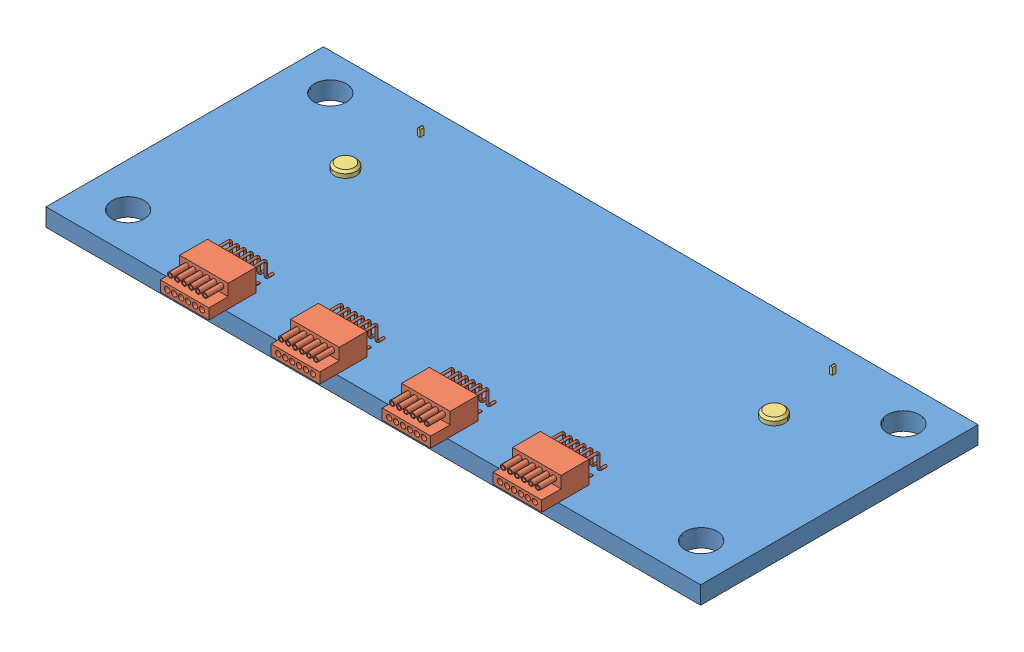
SolidWorks assembly easy connector board asm, configuration Default. Lengths in mm.
Overall size (61.91 9.92 29.94).
6 component instances, 3 part files, 15 mates.
Components (placement in the parent):
- easy connector board-1: easy connector board [Default] at (47.8394 20.0638 41.3103) size (61.91 1.63 29.94)
- A79623-001-1: A79623-001 [Default] at (62.5587 21.6894 51.2163) size (4.45 2.05 6.53)
- A79623-001-2: A79623-001 [Default] at (52.3987 21.6894 51.2163) size (4.45 2.05 6.53)
- A79623-001-3: A79623-001 [Default] at (42.2387 21.6894 51.2163) size (4.45 2.05 6.53)
- A79623-001-4: A79623-001 [Default] at (32.0787 21.6894 51.2163) size (4.45 2.05 6.53)
- samtec female-1: samtec female [Default] at (48.2414 16.6138 40.3413) x (1 0 0) z (0 0 -1) size (45 8.59 11.36)
Mates (geometry in assembly coordinates):
- Coincident1: coincident anti-aligned: plane of easy connector board-1 through (47.8394 21.6894 41.3103) normal (0 1 0); plane of A79623-001-1 through (64.7812 21.6894 51.2163) normal (0 -1 0)
- Distance1: distance = 0.254 mm aligned: plane of easy connector board-1 through (17.8674 21.6894 54.0103) normal (0 0 1); plane of A79623-001-1 through (64.7812 22.6546 53.7563) normal (0 0 1)
- Distance2: distance = 13.0302 mm aligned: plane of A79623-001-1 through (64.7812 21.6894 55.5343) normal (1 0 0); plane of easy connector board-1 through (77.8114 21.6894 28.6103) normal (1 0 0)
- Coincident4: coincident anti-aligned: plane of easy connector board-1 through (47.8394 21.6894 41.3103) normal (0 1 0); plane of A79623-001-2 through (54.6212 21.6894 51.2163) normal (0 -1 0)
- Distance3: distance = 0.254 mm aligned: plane of easy connector board-1 through (17.8674 21.6894 54.0103) normal (0 0 1); plane of A79623-001-2 through (54.6212 22.6546 53.7563) normal (0 0 1)
- Distance8: distance = 23.1902 mm aligned: plane of A79623-001-2 through (54.6212 21.6894 55.5343) normal (1 0 0); plane of easy connector board-1 through (77.8114 21.6894 28.6103) normal (1 0 0)
- Coincident5: coincident anti-aligned: plane of easy connector board-1 through (47.8394 21.6894 41.3103) normal (0 1 0); plane of A79623-001-3 through (44.4612 21.6894 51.2163) normal (0 -1 0)
- Distance9: distance = 0.254 mm aligned: plane of easy connector board-1 through (17.8674 21.6894 54.0103) normal (0 0 1); plane of A79623-001-3 through (44.4612 22.6546 53.7563) normal (0 0 1)
- Distance14: distance = 33.3502 mm aligned: plane of A79623-001-3 through (44.4612 21.6894 55.5343) normal (1 0 0); plane of easy connector board-1 through (77.8114 21.6894 28.6103) normal (1 0 0)
- Coincident6: coincident anti-aligned: plane of easy connector board-1 through (47.8394 21.6894 41.3103) normal (0 1 0); plane of A79623-001-4 through (34.3012 21.6894 51.2163) normal (0 -1 0)
- Distance15: distance = 0.254 mm aligned: plane of easy connector board-1 through (17.8674 21.6894 54.0103) normal (0 0 1); plane of A79623-001-4 through (34.3012 22.6546 53.7563) normal (0 0 1)
- Distance20: distance = 43.5102 mm aligned: plane of A79623-001-4 through (34.3012 21.6894 55.5343) normal (1 0 0); plane of easy connector board-1 through (77.8114 21.6894 28.6103) normal (1 0 0)
- Coincident7: coincident anti-aligned: plane of easy connector board-1 through (47.8394 20.0638 41.3103) normal (0 -1 0); line of samtec female-1 through (70.7414 20.0638 31.9913) axis (-1 0 0)
- Distance21: distance = 0.381 mm aligned: plane of samtec female-1 through (25.7414 20.0638 28.9913) normal (0 0 -1); plane of easy connector board-1 through (17.8674 21.6894 28.6103) normal (0 0 -1)
- Distance22: distance = 7.874 mm aligned: plane of samtec female-1 through (25.7414 13.8138 28.9913) normal (-1 0 0); plane of easy connector board-1 through (17.8674 21.6894 28.6103) normal (-1 0 0)
